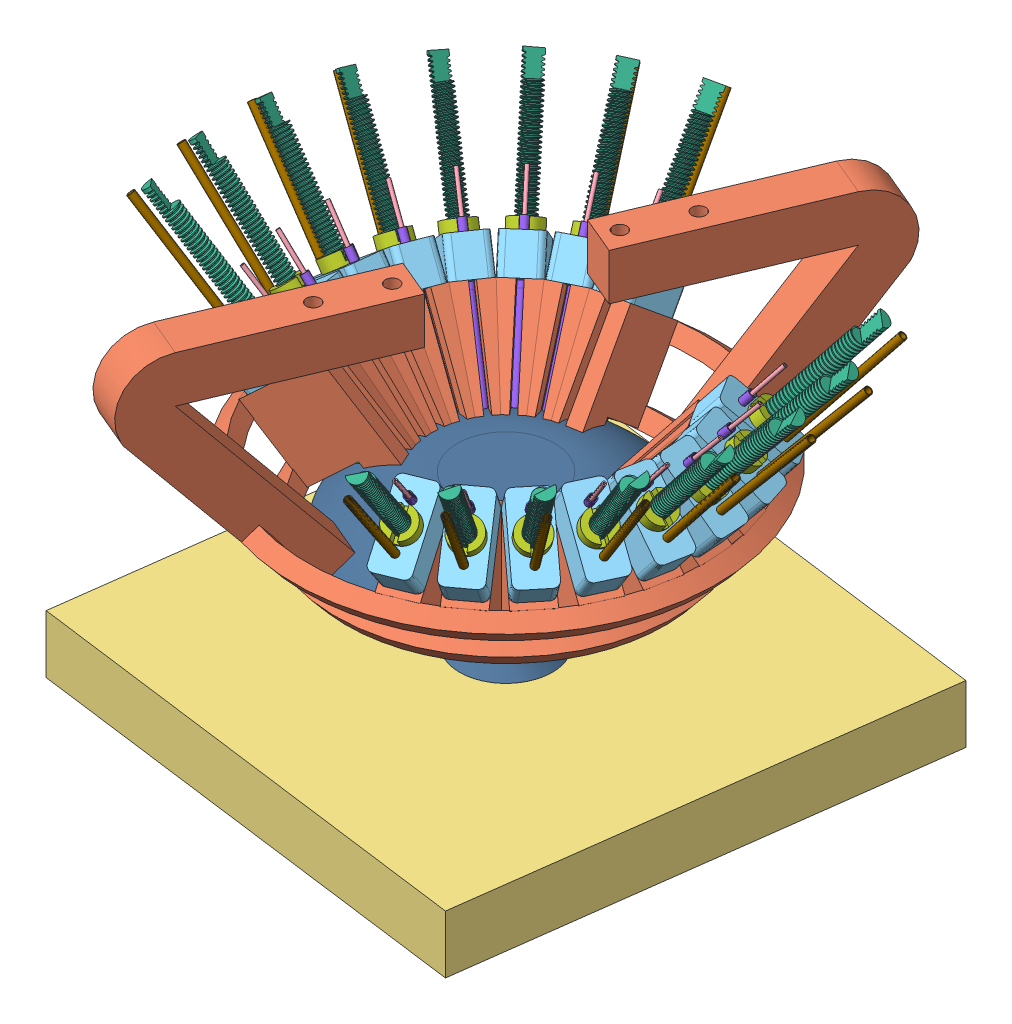
SolidWorks assembly DriveAssembling_Step3, configuration Default. Lengths in mm.
Overall size (52.08 35.24 52.08).
116 component instances, 10 part files, 86 mates.
Components (placement in the parent):
- MainCanula-1: MainCanula [Default] at (-0.6109 2 -0.3095) size (2.41 8 2.41)
- drive_circle_16-1: drive_circle_16 [Default] at (-0.6109 7.8932 -0.3095) x (0.377897 0 0.925848) z (-0.925848 0 0.377897) size (39.95 26.14 39.95)
- SingleCanulaBase-1: SingleCanulaBase [Default] at (-0.6109 0 -0.3095) x (0.991445 0 0.130526) z (-0.130526 0 0.991445) size (40 5 40)
- 30g_curved_long-18: 30g_curved_long [Default] at (-0.577 8 -0.2265) x (0.377897 0 0.925848) z (-0.925848 0 0.377897) size (17.44 28.79 0.32)
- ShuttleAssembly-1: ShuttleAssembly [Default] at (-0.0983 18.931 15.5592) x (-0.289486 0.642788 -0.70924) z (0.925848 0 -0.377897) size (6.5 25.22 3)
  - drive_shuttle-1: drive_shuttle [Default] at (2.5582 1.9761 5.5221) size (6.5 3 3)
  - drive_threaded_rod_25mm-1: drive_threaded_rod_25mm [Default] at (2.5582 -8.5786 5.5221) x (0.813094 0 0.582132) z (-0.582132 0 0.813094) size (1.64 25.22 1.64)
  - Grooved Nut-1: Grooved Nut [Default] at (2.5582 1.9761 5.5221) size (2.5 4 2.5)
  - guide_23g_13mm-1: guide_23g_13mm [Default] at (4.3082 -7.0239 5.5221) size (0.64 13 0.64)
  - stabilizer_23g_25mm-1: stabilizer_23g_25mm [Default] at (0.8082 -8.5786 5.5221) size (0.62 25 0.62)
- 30g_curved_long-23: 30g_curved_long [Default] at (-0.5576 8 -0.2375) x (0.594671 0 0.803969) z (-0.803969 0 0.594671) size (17.44 28.79 0.32)
- ShuttleAssembly-6: ShuttleAssembly [Default] at (3.8016 18.931 14.942) x (-0.455545 0.642788 -0.615876) z (0.803969 0 -0.594671) size (6.5 25.22 3)
  - drive_shuttle-1: drive_shuttle [Default] at (2.5582 1.9761 5.5221) size (6.5 3 3)
  - drive_threaded_rod_25mm-1: drive_threaded_rod_25mm [Default] at (2.5582 -8.5786 5.5221) x (0.813094 0 0.582132) z (-0.582132 0 0.813094) size (1.64 25.22 1.64)
  - Grooved Nut-1: Grooved Nut [Default] at (2.5582 1.9761 5.5221) size (2.5 4 2.5)
  - guide_23g_13mm-1: guide_23g_13mm [Default] at (4.3082 -7.0239 5.5221) size (0.64 13 0.64)
  - stabilizer_23g_25mm-1: stabilizer_23g_25mm [Default] at (0.8082 -8.5786 5.5221) size (0.62 25 0.62)
- 30g_curved_long-24: 30g_curved_long [Default] at (-0.5414 8 -0.2528) x (0.774668 0 0.632368) z (-0.632368 0 0.774668) size (17.44 28.79 0.32)
- ShuttleAssembly-7: ShuttleAssembly [Default] at (7.4286 18.931 13.3816) x (-0.59343 0.642788 -0.484422) z (0.632368 0 -0.774668) size (6.5 25.22 3)
  - drive_shuttle-1: drive_shuttle [Default] at (2.5582 1.9761 5.5221) size (6.5 3 3)
  - drive_threaded_rod_25mm-1: drive_threaded_rod_25mm [Default] at (2.5582 -8.5786 5.5221) x (0.813094 0 0.582132) z (-0.582132 0 0.813094) size (1.64 25.22 1.64)
  - Grooved Nut-1: Grooved Nut [Default] at (2.5582 1.9761 5.5221) size (2.5 4 2.5)
  - guide_23g_13mm-1: guide_23g_13mm [Default] at (4.3082 -7.0239 5.5221) size (0.64 13 0.64)
  - stabilizer_23g_25mm-1: stabilizer_23g_25mm [Default] at (0.8082 -8.5786 5.5221) size (0.62 25 0.62)
- 30g_curved_long-26: 30g_curved_long [Default] at (-0.5296 8 -0.2717) x (0.906755 0 0.421659) z (-0.421659 0 0.906755) size (17.44 28.79 0.32)
- ShuttleAssembly-9: ShuttleAssembly [Default] at (10.5584 18.931 10.9744) x (-0.694614 0.642788 -0.323009) z (0.421659 0 -0.906755) size (6.5 25.22 3)
  - drive_shuttle-1: drive_shuttle [Default] at (2.5582 1.9761 5.5221) size (6.5 3 3)
  - drive_threaded_rod_25mm-1: drive_threaded_rod_25mm [Default] at (2.5582 -8.5786 5.5221) x (0.813094 0 0.582132) z (-0.582132 0 0.813094) size (1.64 25.22 1.64)
  - Grooved Nut-1: Grooved Nut [Default] at (2.5582 1.9761 5.5221) size (2.5 4 2.5)
  - guide_23g_13mm-1: guide_23g_13mm [Default] at (4.3082 -7.0239 5.5221) size (0.64 13 0.64)
  - stabilizer_23g_25mm-1: stabilizer_23g_25mm [Default] at (0.8082 -8.5786 5.5221) size (0.62 25 0.62)
- 30g_curved_long-27: 30g_curved_long [Default] at (-0.5228 8 -0.293) x (0.982763 0 0.184872) z (-0.184872 0 0.982763) size (17.44 28.79 0.32)
- ShuttleAssembly-10: ShuttleAssembly [Default] at (12.9974 18.931 7.8694) x (-0.75284 0.642788 -0.14162) z (0.184872 0 -0.982763) size (6.5 25.22 3)
  - drive_shuttle-1: drive_shuttle [Default] at (2.5582 1.9761 5.5221) size (6.5 3 3)
  - drive_threaded_rod_25mm-1: drive_threaded_rod_25mm [Default] at (2.5582 -8.5786 5.5221) x (0.813094 0 0.582132) z (-0.582132 0 0.813094) size (1.64 25.22 1.64)
  - Grooved Nut-1: Grooved Nut [Default] at (2.5582 1.9761 5.5221) size (2.5 4 2.5)
  - guide_23g_13mm-1: guide_23g_13mm [Default] at (4.3082 -7.0239 5.5221) size (0.64 13 0.64)
  - stabilizer_23g_25mm-1: stabilizer_23g_25mm [Default] at (0.8082 -8.5786 5.5221) size (0.62 25 0.62)
- 30g_curved_long-28: 30g_curved_long [Default] at (-0.5214 8 -0.3152) x (0.997991 0 -0.063349) z (0.063349 0 0.997991) size (17.44 28.79 0.32)
- ShuttleAssembly-11: ShuttleAssembly [Default] at (14.5948 18.931 4.2585) x (-0.764506 0.642788 0.048528) z (-0.063349 0 -0.997991) size (6.5 25.22 3)
  - drive_shuttle-1: drive_shuttle [Default] at (2.5582 1.9761 5.5221) size (6.5 3 3)
  - drive_threaded_rod_25mm-1: drive_threaded_rod_25mm [Default] at (2.5582 -8.5786 5.5221) x (0.813094 0 0.582132) z (-0.582132 0 0.813094) size (1.64 25.22 1.64)
  - Grooved Nut-1: Grooved Nut [Default] at (2.5582 1.9761 5.5221) size (2.5 4 2.5)
  - guide_23g_13mm-1: guide_23g_13mm [Default] at (4.3082 -7.0239 5.5221) size (0.64 13 0.64)
  - stabilizer_23g_25mm-1: stabilizer_23g_25mm [Default] at (0.8082 -8.5786 5.5221) size (0.62 25 0.62)
- 30g_curved_long-29: 30g_curved_long [Default] at (-0.5256 8 -0.3371) x (0.951499 0 -0.307652) z (0.307652 0 0.951499) size (17.44 28.79 0.32)
- ShuttleAssembly-12: ShuttleAssembly [Default] at (15.2518 18.931 0.3651) x (-0.728891 0.642788 0.235675) z (-0.307652 0 -0.951499) size (6.5 25.22 3)
  - drive_shuttle-1: drive_shuttle [Default] at (2.5582 1.9761 5.5221) size (6.5 3 3)
  - drive_threaded_rod_25mm-1: drive_threaded_rod_25mm [Default] at (2.5582 -8.5786 5.5221) x (0.813094 0 0.582132) z (-0.582132 0 0.813094) size (1.64 25.22 1.64)
  - Grooved Nut-1: Grooved Nut [Default] at (2.5582 1.9761 5.5221) size (2.5 4 2.5)
  - guide_23g_13mm-1: guide_23g_13mm [Default] at (4.3082 -7.0239 5.5221) size (0.64 13 0.64)
  - stabilizer_23g_25mm-1: stabilizer_23g_25mm [Default] at (0.8082 -8.5786 5.5221) size (0.62 25 0.62)
- 30g_curved_long-30: 30g_curved_long [Default] at (-0.535 8 -0.3573) x (0.846161 0 -0.532928) z (0.532928 0 0.846161) size (17.44 28.79 0.32)
- ShuttleAssembly-13: ShuttleAssembly [Default] at (14.9278 18.931 -3.5699) x (-0.648197 0.642788 0.408246) z (-0.532928 0 -0.846161) size (6.5 25.22 3)
  - drive_shuttle-1: drive_shuttle [Default] at (2.5582 1.9761 5.5221) size (6.5 3 3)
  - drive_threaded_rod_25mm-1: drive_threaded_rod_25mm [Default] at (2.5582 -8.5786 5.5221) x (0.813094 0 0.582132) z (-0.582132 0 0.813094) size (1.64 25.22 1.64)
  - Grooved Nut-1: Grooved Nut [Default] at (2.5582 1.9761 5.5221) size (2.5 4 2.5)
  - guide_23g_13mm-1: guide_23g_13mm [Default] at (4.3082 -7.0239 5.5221) size (0.64 13 0.64)
  - stabilizer_23g_25mm-1: stabilizer_23g_25mm [Default] at (0.8082 -8.5786 5.5221) size (0.62 25 0.62)
- 30g_curved_long-42: 30g_curved_long [Default] at (-0.6298 8 -0.3972) x (-0.211384 0 -0.977403) z (0.977403 0 -0.211384) size (17.44 28.79 0.32)
- ShuttleAssembly-25: ShuttleAssembly [Default] at (1.6399 18.931 -16.0262) x (0.16193 0.642788 0.748734) z (-0.977403 0 0.211384) size (6.5 25.22 3)
  - drive_shuttle-1: drive_shuttle [Default] at (2.5582 1.9761 5.5221) size (6.5 3 3)
  - drive_threaded_rod_25mm-1: drive_threaded_rod_25mm [Default] at (2.5582 -8.5786 5.5221) x (0.813094 0 0.582132) z (-0.582132 0 0.813094) size (1.64 25.22 1.64)
  - Grooved Nut-1: Grooved Nut [Default] at (2.5582 1.9761 5.5221) size (2.5 4 2.5)
  - guide_23g_13mm-1: guide_23g_13mm [Default] at (4.3082 -7.0239 5.5221) size (0.64 13 0.64)
  - stabilizer_23g_25mm-1: stabilizer_23g_25mm [Default] at (0.8082 -8.5786 5.5221) size (0.62 25 0.62)
- 30g_curved_long-43: 30g_curved_long [Default] at (-0.6509 8 -0.3898) x (-0.446029 0 -0.895018) z (0.895018 0 -0.446029) size (17.44 28.79 0.32)
- ShuttleAssembly-26: ShuttleAssembly [Default] at (-2.3079 18.931 -16.0956) x (0.341678 0.642788 0.685624) z (-0.895018 0 0.446029) size (6.5 25.22 3)
  - drive_shuttle-1: drive_shuttle [Default] at (2.5582 1.9761 5.5221) size (6.5 3 3)
  - drive_threaded_rod_25mm-1: drive_threaded_rod_25mm [Default] at (2.5582 -8.5786 5.5221) x (0.813094 0 0.582132) z (-0.582132 0 0.813094) size (1.64 25.22 1.64)
  - Grooved Nut-1: Grooved Nut [Default] at (2.5582 1.9761 5.5221) size (2.5 4 2.5)
  - guide_23g_13mm-1: guide_23g_13mm [Default] at (4.3082 -7.0239 5.5221) size (0.64 13 0.64)
  - stabilizer_23g_25mm-1: stabilizer_23g_25mm [Default] at (0.8082 -8.5786 5.5221) size (0.62 25 0.62)
- 30g_curved_long-44: 30g_curved_long [Default] at (-0.6694 8 -0.3774) x (-0.653089 0 -0.757281) z (0.757281 0 -0.653089) size (17.44 28.79 0.32)
- ShuttleAssembly-27: ShuttleAssembly [Default] at (-6.1508 18.931 -15.1887) x (0.500295 0.642788 0.580111) z (-0.757281 0 0.653089) size (6.5 25.22 3)
  - drive_shuttle-1: drive_shuttle [Default] at (2.5582 1.9761 5.5221) size (6.5 3 3)
  - drive_threaded_rod_25mm-1: drive_threaded_rod_25mm [Default] at (2.5582 -8.5786 5.5221) x (0.813094 0 0.582132) z (-0.582132 0 0.813094) size (1.64 25.22 1.64)
  - Grooved Nut-1: Grooved Nut [Default] at (2.5582 1.9761 5.5221) size (2.5 4 2.5)
  - guide_23g_13mm-1: guide_23g_13mm [Default] at (4.3082 -7.0239 5.5221) size (0.64 13 0.64)
  - stabilizer_23g_25mm-1: stabilizer_23g_25mm [Default] at (0.8082 -8.5786 5.5221) size (0.62 25 0.62)
- 30g_curved_long-45: 30g_curved_long [Default] at (-0.6844 8 -0.3609) x (-0.819759 0 -0.572709) z (0.572709 0 -0.819759) size (17.44 28.79 0.32)
- ShuttleAssembly-28: ShuttleAssembly [Default] at (-9.651 18.931 -13.3616) x (0.627971 0.642788 0.438721) z (-0.572709 0 0.819759) size (6.5 25.22 3)
  - drive_shuttle-1: drive_shuttle [Default] at (2.5582 1.9761 5.5221) size (6.5 3 3)
  - drive_threaded_rod_25mm-1: drive_threaded_rod_25mm [Default] at (2.5582 -8.5786 5.5221) x (0.813094 0 0.582132) z (-0.582132 0 0.813094) size (1.64 25.22 1.64)
  - Grooved Nut-1: Grooved Nut [Default] at (2.5582 1.9761 5.5221) size (2.5 4 2.5)
  - guide_23g_13mm-1: guide_23g_13mm [Default] at (4.3082 -7.0239 5.5221) size (0.64 13 0.64)
  - stabilizer_23g_25mm-1: stabilizer_23g_25mm [Default] at (0.8082 -8.5786 5.5221) size (0.62 25 0.62)
- 30g_curved_long-49: 30g_curved_long [Default] at (-0.6948 8 -0.3412) x (-0.93573 0 -0.352718) z (0.352718 0 -0.93573) size (17.44 28.79 0.32)
- ShuttleAssembly-32: ShuttleAssembly [Default] at (-12.5922 18.931 -10.7272) x (0.716811 0.642788 0.270198) z (-0.352718 0 0.93573) size (6.5 25.22 3)
  - drive_shuttle-1: drive_shuttle [Default] at (2.5582 1.9761 5.5221) size (6.5 3 3)
  - drive_threaded_rod_25mm-1: drive_threaded_rod_25mm [Default] at (2.5582 -8.5786 5.5221) x (0.813094 0 0.582132) z (-0.582132 0 0.813094) size (1.64 25.22 1.64)
  - Grooved Nut-1: Grooved Nut [Default] at (2.5582 1.9761 5.5221) size (2.5 4 2.5)
  - guide_23g_13mm-1: guide_23g_13mm [Default] at (4.3082 -7.0239 5.5221) size (0.64 13 0.64)
  - stabilizer_23g_25mm-1: stabilizer_23g_25mm [Default] at (0.8082 -8.5786 5.5221) size (0.62 25 0.62)
- 30g_curved_long-50: 30g_curved_long [Default] at (-0.7 8 -0.3195) x (-0.99383 0 -0.110913) z (0.110913 0 -0.99383) size (17.44 28.79 0.32)
- ShuttleAssembly-33: ShuttleAssembly [Default] at (-14.7923 18.931 -7.4486) x (0.761318 0.642788 0.084964) z (-0.110913 0 0.99383) size (6.5 25.22 3)
  - drive_shuttle-1: drive_shuttle [Default] at (2.5582 1.9761 5.5221) size (6.5 3 3)
  - drive_threaded_rod_25mm-1: drive_threaded_rod_25mm [Default] at (2.5582 -8.5786 5.5221) x (0.813094 0 0.582132) z (-0.582132 0 0.813094) size (1.64 25.22 1.64)
  - Grooved Nut-1: Grooved Nut [Default] at (2.5582 1.9761 5.5221) size (2.5 4 2.5)
  - guide_23g_13mm-1: guide_23g_13mm [Default] at (4.3082 -7.0239 5.5221) size (0.64 13 0.64)
  - stabilizer_23g_25mm-1: stabilizer_23g_25mm [Default] at (0.8082 -8.5786 5.5221) size (0.62 25 0.62)
- 30g_curved_long-51: 30g_curved_long [Default] at (-0.6997 8 -0.2972) x (-0.990467 0 0.137752) z (-0.137752 0 -0.990467) size (17.44 28.79 0.32)
- ShuttleAssembly-34: ShuttleAssembly [Default] at (-16.1154 18.931 -3.7285) x (0.758742 0.642788 -0.105524) z (0.137752 0 0.990467) size (6.5 25.22 3)
  - drive_shuttle-1: drive_shuttle [Default] at (2.5582 1.9761 5.5221) size (6.5 3 3)
  - drive_threaded_rod_25mm-1: drive_threaded_rod_25mm [Default] at (2.5582 -8.5786 5.5221) x (0.813094 0 0.582132) z (-0.582132 0 0.813094) size (1.64 25.22 1.64)
  - Grooved Nut-1: Grooved Nut [Default] at (2.5582 1.9761 5.5221) size (2.5 4 2.5)
  - guide_23g_13mm-1: guide_23g_13mm [Default] at (4.3082 -7.0239 5.5221) size (0.64 13 0.64)
  - stabilizer_23g_25mm-1: stabilizer_23g_25mm [Default] at (0.8082 -8.5786 5.5221) size (0.62 25 0.62)
- 30g_curved_long-52: 30g_curved_long [Default] at (-0.6939 8 -0.2757) x (-0.925848 0 0.377897) z (-0.377897 0 -0.925848) size (17.44 28.79 0.32)
- ShuttleAssembly-35: ShuttleAssembly [Default] at (-16.4796 18.931 0.2031) x (0.70924 0.642788 -0.289486) z (0.377897 0 0.925848) size (6.5 25.22 3)
  - drive_shuttle-1: drive_shuttle [Default] at (2.5582 1.9761 5.5221) size (6.5 3 3)
  - drive_threaded_rod_25mm-1: drive_threaded_rod_25mm [Default] at (2.5582 -8.5786 5.5221) x (0.813094 0 0.582132) z (-0.582132 0 0.813094) size (1.64 25.22 1.64)
  - Grooved Nut-1: Grooved Nut [Default] at (2.5582 1.9761 5.5221) size (2.5 4 2.5)
  - guide_23g_13mm-1: guide_23g_13mm [Default] at (4.3082 -7.0239 5.5221) size (0.64 13 0.64)
  - stabilizer_23g_25mm-1: stabilizer_23g_25mm [Default] at (0.8082 -8.5786 5.5221) size (0.62 25 0.62)
- AcrylicFill-Larger-Bottom-1: AcrylicFill-Larger-Bottom [Default] at (-0.6109 9 -0.3095) x (0.994633 0 0.10347) z (-0.10347 0 0.994633) size (24 13.01 24)
Mates (geometry in assembly coordinates):
- Concentric3: concentric aligned: circle of MainCanula-1; circle of SingleCanulaBase-1
- Coincident3: coincident aligned: plane of MainCanula-1 through (-0.6109 0 -0.3095) normal (0 -1 0); plane of SingleCanulaBase-1 through (-0.6109 0 -0.3095) normal (0 -1 0)
- Coincident6-30g, bottom: coincident anti-aligned: plane of 30g_curved_long-18 through (-0.5014 0 -0.0414) normal (0 -1 0); plane of assembly through (0 0 0) normal (0 1 0)
- Concentric6-guidetube: concentric aligned: circle of drive_circle_16-1; circle of 30g_curved_long-18
- Concentric7-stabilizer: concentric aligned: circle of drive_circle_16-1; circle of ShuttleAssembly-1/stabilizer_23g_25mm-1
- Concentric8-30g: concentric aligned: circle of 30g_curved_long-18; circle of ShuttleAssembly-1/guide_23g_13mm-1
- Coincident10 - FlushShuttle: coincident anti-aligned: plane of drive_circle_16-1 through (5.2018 24.1782 9.9622) normal (0.242908 0.766044 0.595123); plane of ShuttleAssembly-1/drive_shuttle-1 through (4.7539 22.0892 12.8341) normal (-0.242908 -0.766044 -0.595123)
- Concentric9: concentric anti-aligned: circle of MainCanula-1; circle of drive_circle_16-1
- Concentric20: concentric aligned: circle of 30g_curved_long-23; circle of ShuttleAssembly-6/guide_23g_13mm-1
- Coincident10: coincident anti-aligned: plane of 30g_curved_long-23 through (-0.4386 0 -0.0767) normal (0 -1 0); plane of assembly through (0 0 0) normal (0 1 0)
- Concentric21: concentric aligned: circle of drive_circle_16-1; circle of 30g_curved_long-23
- Concentric22: concentric aligned: circle of drive_circle_16-1; circle of ShuttleAssembly-6/stabilizer_23g_25mm-1
- Coincident11: coincident anti-aligned: plane of drive_circle_16-1 through (7.5567 24.1782 8.2103) normal (0.382247 0.766044 0.516781); plane of ShuttleAssembly-6/drive_shuttle-1 through (7.8313 22.0892 11.1039) normal (-0.382247 -0.766044 -0.516781)
- Concentric23: concentric aligned: circle of 30g_curved_long-24; circle of ShuttleAssembly-7/guide_23g_13mm-1
- Coincident12: coincident anti-aligned: plane of 30g_curved_long-24 through (-0.3865 0 -0.1264) normal (0 -1 0); plane of assembly through (0 0 0) normal (0 1 0)
- Concentric24: concentric aligned: circle of drive_circle_16-1; circle of 30g_curved_long-24
- Concentric25: concentric aligned: circle of drive_circle_16-1; circle of ShuttleAssembly-7/stabilizer_23g_25mm-1
- Coincident13: coincident anti-aligned: plane of drive_circle_16-1 through (9.4065 24.1782 5.9314) normal (0.497947 0.766044 0.406479); plane of ShuttleAssembly-7/drive_shuttle-1 through (10.3866 22.0892 8.6678) normal (-0.497947 -0.766044 -0.406479)
- Concentric29: concentric aligned: circle of 30g_curved_long-26; circle of ShuttleAssembly-9/guide_23g_13mm-1
- Coincident16: coincident anti-aligned: plane of 30g_curved_long-26 through (-0.3482 0 -0.1874) normal (0 -1 0); plane of assembly through (0 0 0) normal (0 1 0)
- Concentric30: concentric aligned: circle of drive_circle_16-1; circle of 30g_curved_long-26
- Concentric31: concentric aligned: circle of drive_circle_16-1; circle of ShuttleAssembly-9/stabilizer_23g_25mm-1
- Coincident17: coincident anti-aligned: plane of drive_circle_16-1 through (10.6367 24.1782 3.2666) normal (0.582851 0.766044 0.271037); plane of ShuttleAssembly-9/drive_shuttle-1 through (12.2617 22.0892 5.6765) normal (-0.582851 -0.766044 -0.271037)
- Concentric32: concentric aligned: circle of 30g_curved_long-27; circle of ShuttleAssembly-10/guide_23g_13mm-1
- Coincident18: coincident anti-aligned: plane of 30g_curved_long-27 through (-0.3262 0 -0.256) normal (0 -1 0); plane of assembly through (0 0 0) normal (0 1 0)
- Concentric33: concentric aligned: circle of drive_circle_16-1; circle of 30g_curved_long-27
- Concentric34: concentric aligned: circle of drive_circle_16-1; circle of ShuttleAssembly-10/stabilizer_23g_25mm-1
- Coincident20: coincident anti-aligned: plane of drive_circle_16-1 through (11.1713 24.1782 0.3806) normal (0.631708 0.766044 0.118833); plane of ShuttleAssembly-10/drive_shuttle-1 through (13.3407 22.0892 2.315) normal (-0.631708 -0.766044 -0.118833)
- Concentric35: concentric aligned: circle of 30g_curved_long-28; circle of ShuttleAssembly-11/guide_23g_13mm-1
- Coincident21: coincident anti-aligned: plane of 30g_curved_long-28 through (-0.3218 0 -0.3279) normal (0 -1 0); plane of assembly through (0 0 0) normal (0 1 0)
- Concentric36: concentric aligned: circle of drive_circle_16-1; circle of 30g_curved_long-28
- Concentric37: concentric aligned: circle of drive_circle_16-1; circle of ShuttleAssembly-11/stabilizer_23g_25mm-1
- Coincident22: coincident anti-aligned: plane of drive_circle_16-1 through (10.9773 24.1782 -2.5481) normal (0.641497 0.766044 -0.04072); plane of ShuttleAssembly-11/drive_shuttle-1 through (13.5569 22.0892 -1.2089) normal (-0.641497 -0.766044 0.04072)
- Concentric38: concentric aligned: circle of 30g_curved_long-29; circle of ShuttleAssembly-12/guide_23g_13mm-1
- Coincident23: coincident anti-aligned: plane of 30g_curved_long-29 through (-0.3353 0 -0.3986) normal (0 -1 0); plane of assembly through (0 0 0) normal (0 1 0)
- Concentric39: concentric aligned: circle of drive_circle_16-1; circle of 30g_curved_long-29
- Concentric40: concentric aligned: circle of drive_circle_16-1; circle of ShuttleAssembly-12/stabilizer_23g_25mm-1
- Coincident24: coincident anti-aligned: plane of drive_circle_16-1 through (10.0665 24.1782 -5.3384) normal (0.611612 0.766044 -0.197755); plane of ShuttleAssembly-12/drive_shuttle-1 through (12.8969 22.0892 -4.6771) normal (-0.611612 -0.766044 0.197755)
- Concentric41: concentric aligned: circle of 30g_curved_long-30; circle of ShuttleAssembly-13/guide_23g_13mm-1
- Coincident25: coincident anti-aligned: plane of 30g_curved_long-30 through (-0.3658 0 -0.4639) normal (0 -1 0); plane of assembly through (0 0 0) normal (0 1 0)
- Concentric42: concentric aligned: circle of drive_circle_16-1; circle of 30g_curved_long-30
- Concentric43: concentric aligned: circle of drive_circle_16-1; circle of ShuttleAssembly-13/stabilizer_23g_25mm-1
- Coincident27: coincident anti-aligned: plane of drive_circle_16-1 through (8.4955 24.1782 -7.8176) normal (0.543902 0.766044 -0.342559); plane of ShuttleAssembly-13/drive_shuttle-1 through (11.4015 22.0892 -7.8752) normal (-0.543902 -0.766044 0.342559)
- Concentric66: concentric anti-aligned: circle of 30g_curved_long-42; circle of drive_circle_16-1
- Coincident41: coincident anti-aligned: plane of assembly through (0 0 0) normal (0 1 0); plane of 30g_curved_long-42 through (-0.6721 0 -0.5926) normal (0 -1 0)
- Concentric67: concentric aligned: circle of 30g_curved_long-42; circle of ShuttleAssembly-25/guide_23g_13mm-1
- Concentric68: concentric anti-aligned: circle of drive_circle_16-1; circle of ShuttleAssembly-25/stabilizer_23g_25mm-1
- Coincident42: coincident anti-aligned: plane of drive_circle_16-1 through (-1.6194 24.1782 -12.0688) normal (-0.135875 0.766044 -0.628263); plane of ShuttleAssembly-25/drive_shuttle-1 through (-3.6118 22.0892 -14.1851) normal (0.135875 -0.766044 0.628263)
- Concentric69: concentric aligned: circle of 30g_curved_long-43; circle of ShuttleAssembly-26/guide_23g_13mm-1
- Concentric70: concentric anti-aligned: circle of drive_circle_16-1; circle of 30g_curved_long-43
- Coincident43: coincident anti-aligned: plane of 30g_curved_long-43 through (-0.7401 0 -0.5688) normal (0 -1 0); plane of assembly through (0 0 0) normal (0 1 0)
- Concentric71: concentric anti-aligned: circle of drive_circle_16-1; circle of ShuttleAssembly-26/stabilizer_23g_25mm-1
- Coincident44: coincident anti-aligned: plane of drive_circle_16-1 through (-4.4899 24.1782 -11.4563) normal (-0.286702 0.766044 -0.575307); plane of ShuttleAssembly-26/drive_shuttle-1 through (-6.9429 22.0892 -13.0155) normal (0.286702 -0.766044 0.575307)
- Concentric72: concentric aligned: circle of 30g_curved_long-44; circle of ShuttleAssembly-27/guide_23g_13mm-1
- Concentric73: concentric anti-aligned: circle of drive_circle_16-1; circle of 30g_curved_long-44
- Coincident45: coincident anti-aligned: plane of assembly through (0 0 0) normal (0 1 0); plane of 30g_curved_long-44 through (-0.8 0 -0.5289) normal (0 -1 0)
- Concentric74: concentric anti-aligned: circle of drive_circle_16-1; circle of ShuttleAssembly-27/stabilizer_23g_25mm-1
- Coincident46: coincident anti-aligned: plane of drive_circle_16-1 through (-7.1205 24.1782 -10.1544) normal (-0.419798 0.766044 -0.486771); plane of ShuttleAssembly-27/drive_shuttle-1 through (-9.8824 22.0892 -11.0601) normal (0.419798 -0.766044 0.486771)
- Concentric75: concentric aligned: circle of 30g_curved_long-45; circle of ShuttleAssembly-28/guide_23g_13mm-1
- Concentric76: concentric anti-aligned: circle of drive_circle_16-1; circle of 30g_curved_long-45
- Coincident47: coincident anti-aligned: plane of assembly through (0 0 0) normal (0 1 0); plane of 30g_curved_long-45 through (-0.8483 0 -0.4754) normal (0 -1 0)
- Concentric77: concentric anti-aligned: circle of drive_circle_16-1; circle of ShuttleAssembly-28/stabilizer_23g_25mm-1
- Coincident48: coincident anti-aligned: plane of drive_circle_16-1 through (-9.3485 24.1782 -8.2437) normal (-0.526931 0.766044 -0.36813); plane of ShuttleAssembly-28/drive_shuttle-1 through (-12.2484 22.0892 -8.4399) normal (0.526931 -0.766044 0.36813)
- Coincident49: coincident anti-aligned: plane of assembly through (0 0 0) normal (0 1 0); plane of 30g_curved_long-43 through (-0.7401 0 -0.5688) normal (0 -1 0)
- Concentric82: concentric aligned: circle of 30g_curved_long-49; circle of ShuttleAssembly-32/guide_23g_13mm-1
- Concentric83: concentric anti-aligned: circle of drive_circle_16-1; circle of 30g_curved_long-49
- Coincident54: coincident aligned: plane of 30g_curved_long-43 through (-0.7401 0 -0.5688) normal (0 -1 0); plane of 30g_curved_long-49 through (-0.8819 0 -0.4117) normal (0 -1 0)
- Concentric84: concentric anti-aligned: circle of drive_circle_16-1; circle of ShuttleAssembly-32/stabilizer_23g_25mm-1
- Coincident55: coincident anti-aligned: plane of drive_circle_16-1 through (-11.0361 24.1782 -5.8423) normal (-0.601475 0.766044 -0.226723); plane of ShuttleAssembly-32/drive_shuttle-1 through (-13.8948 22.0892 -5.3168) normal (0.601475 -0.766044 0.226723)
- Concentric85: concentric aligned: circle of 30g_curved_long-50; circle of ShuttleAssembly-33/guide_23g_13mm-1
- Concentric86: concentric anti-aligned: circle of drive_circle_16-1; circle of 30g_curved_long-50
- Coincident56: coincident aligned: plane of 30g_curved_long-43 through (-0.7401 0 -0.5688) normal (0 -1 0); plane of 30g_curved_long-50 through (-0.8987 0 -0.3417) normal (0 -1 0)
- Concentric87: concentric anti-aligned: circle of drive_circle_16-1; circle of ShuttleAssembly-33/stabilizer_23g_25mm-1
- Coincident57: coincident anti-aligned: plane of drive_circle_16-1 through (-12.079 24.1782 -3.0987) normal (-0.638822 0.766044 -0.071293); plane of ShuttleAssembly-33/drive_shuttle-1 through (-14.7196 22.0892 -1.8841) normal (0.638822 -0.766044 0.071293)
- Concentric88: concentric aligned: circle of 30g_curved_long-51; circle of ShuttleAssembly-34/guide_23g_13mm-1
- Concentric89: concentric anti-aligned: circle of drive_circle_16-1; circle of 30g_curved_long-51
- Coincident58: coincident aligned: plane of 30g_curved_long-43 through (-0.7401 0 -0.5688) normal (0 -1 0); plane of 30g_curved_long-51 through (-0.8978 0 -0.2696) normal (0 -1 0)
- Concentric90: concentric anti-aligned: circle of drive_circle_16-1; circle of ShuttleAssembly-34/stabilizer_23g_25mm-1
- Coincident59: coincident anti-aligned: plane of drive_circle_16-1 through (-12.4126 24.1782 -0.1826) normal (-0.63666 0.766044 0.088545); plane of ShuttleAssembly-34/drive_shuttle-1 through (-14.6719 22.0892 1.646) normal (0.63666 -0.766044 -0.088545)
- Concentric91: concentric aligned: circle of 30g_curved_long-52; circle of ShuttleAssembly-35/guide_23g_13mm-1
- Concentric92: concentric anti-aligned: circle of drive_circle_16-1; circle of 30g_curved_long-52
- Coincident60: coincident aligned: plane of 30g_curved_long-43 through (-0.7401 0 -0.5688) normal (0 -1 0); plane of 30g_curved_long-52 through (-0.8791 0 -0.2001) normal (0 -1 0)
- Concentric93: concentric anti-aligned: circle of drive_circle_16-1; circle of ShuttleAssembly-35/stabilizer_23g_25mm-1
- Coincident61: coincident anti-aligned: plane of drive_circle_16-1 through (-12.0163 24.1782 2.7256) normal (-0.595123 0.766044 0.242908); plane of ShuttleAssembly-35/drive_shuttle-1 through (-13.7545 22.0892 5.0552) normal (0.595123 -0.766044 -0.242908)
- Concentric94: concentric aligned: circle of drive_circle_16-1; circle of AcrylicFill-Larger-Bottom-1
- Coincident62: coincident anti-aligned: plane of SingleCanulaBase-1 through (-0.6109 5 -0.3095) normal (0 1 0); circle of AcrylicFill-Larger-Bottom-1
